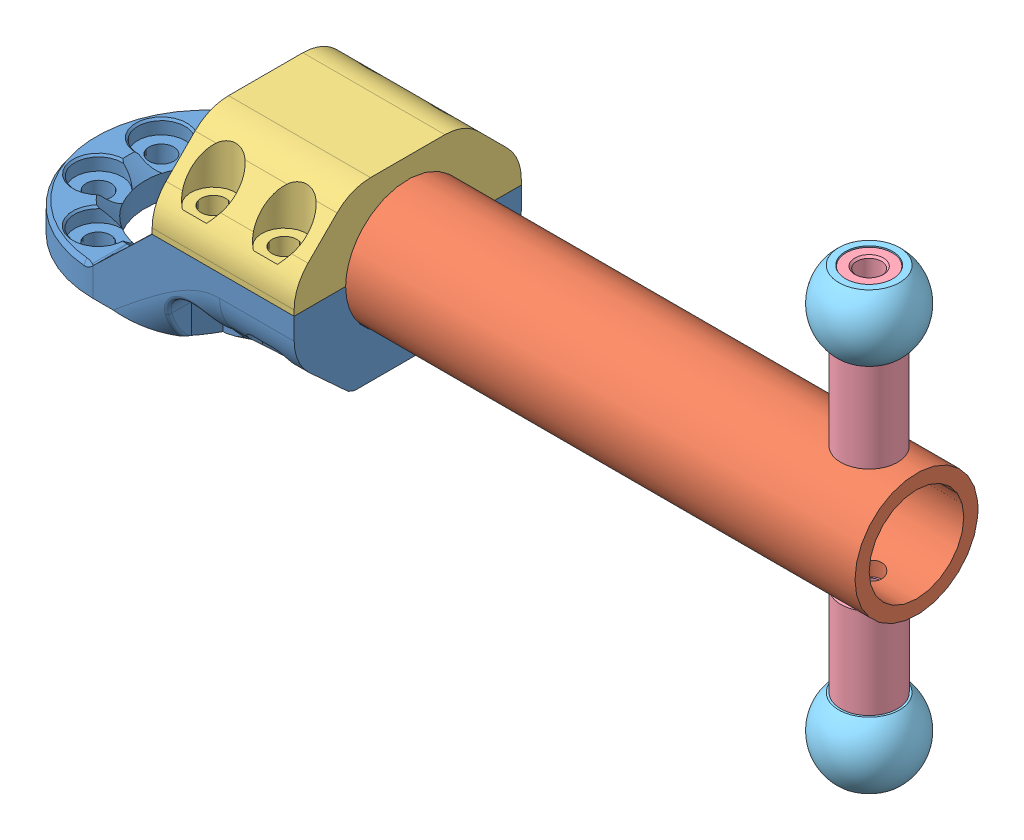
SolidWorks assembly proximal-link, configuration Default. Lengths in mm.
Overall size (174 92.2 48.61).
8 component instances, 5 part files, 0 mates.
Components (placement in the parent):
- Proximal link^proximal-link-2: Proximal link^proximal-link [Default] at origin size (174 92.2 48.61) (virtual)
  - revolute-joint-1: revolute-joint [Default] at (-15.5275 13.2063 -4.1675) size (66.5 20.7 48.61)
  - proximal-link-1: proximal-link [Default] at (-3.0275 33.2063 -4.1675) x (0 0 -1) z (1 0 0) size (26 26 137.5)
  - joint-clamp-1: joint-clamp [Default] at (-3.0275 41.7563 -4.155) x (0 0 -1) z (1 0 0) size (48 17.3 30)
  - connection-tap-joint-1: connection-tap-joint [Default] at (124.4725 79.1063 -4.1675) x (0.500772 0 0.865579) z (0.865579 0 -0.500772) size (12 32.9 12)
  - connection-tap-joint-2: connection-tap-joint [Default] at (124.4725 -12.6937 -4.1675) x (0.550483 0 -0.834846) z (0.834846 0 0.550483) size (12 32.9 12)
  - distal-link-sphere-1: distal-link-sphere [Default] at (124.4725 72.3063 -4.1675) size (19 14 19)
  - distal-link-sphere-2: distal-link-sphere [Default] at (124.4725 -5.8937 -4.1675) size (19 14 19)
